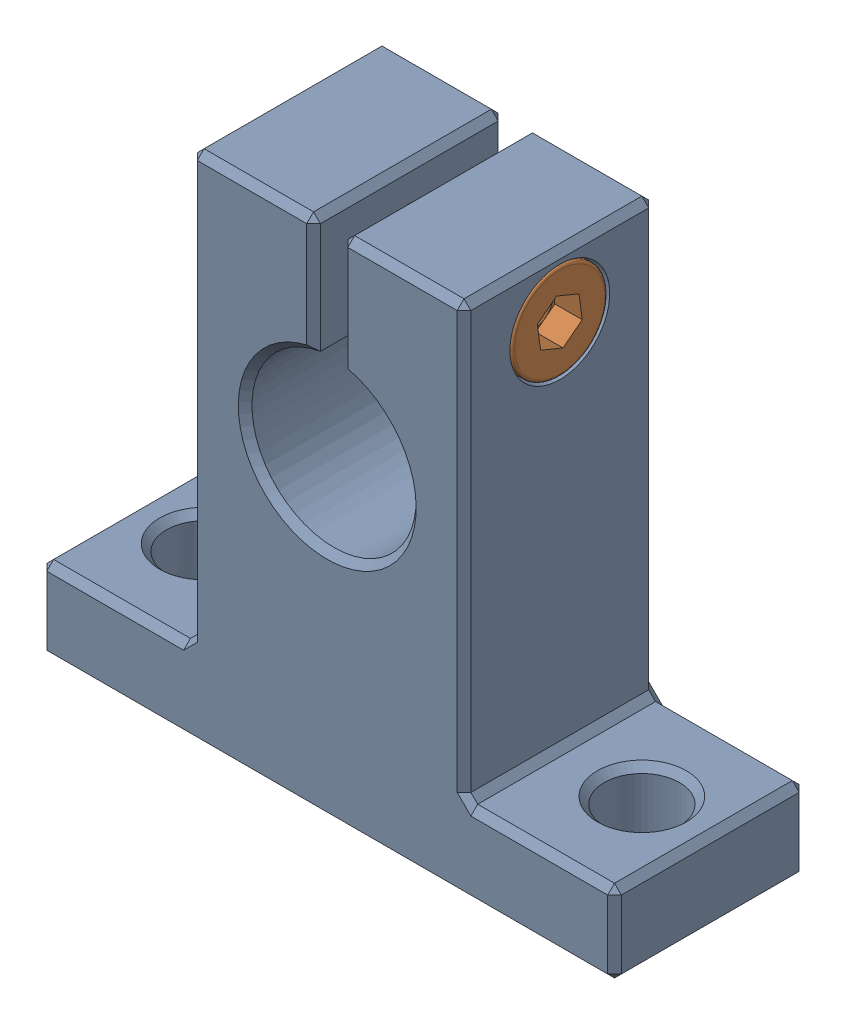
SolidWorks assembly EspelharSK12, configuration Valor predeterminado. Lengths in mm.
Overall size (42 37.6 14).
2 component instances, 2 part files, 2 mates.
Components (placement in the parent):
- EspelharShaft support SK12-1: EspelharShaft support SK12 [Valor predeterminado] at (-5.6953 6.0163 -42) size (42 37.5 14)
- Espelharm4x16-1: Espelharm4x16 [Valor predeterminado] at (4.3047 16.0441 -42) x (-1 0 0) z (0 -0.924225 0.381849) size (20 7 7)
Mates (geometry in assembly coordinates):
- Concêntrico1: concentric aligned: cylinder of EspelharShaft support SK12-1 through (4.3047 16.0441 -42) axis (1 0 0) radius 3.65; cylinder of Espelharm4x16-1 through (0.3047 16.0441 -42) axis (1 0 0) radius 3.5
- Coincidente1: coincident anti-aligned: plane of EspelharShaft support SK12-1 through (0.3047 17.7441 -42) normal (1 0 0); plane of Espelharm4x16-1 through (0.3047 14.7076 -45.2348) normal (-1 0 0)
